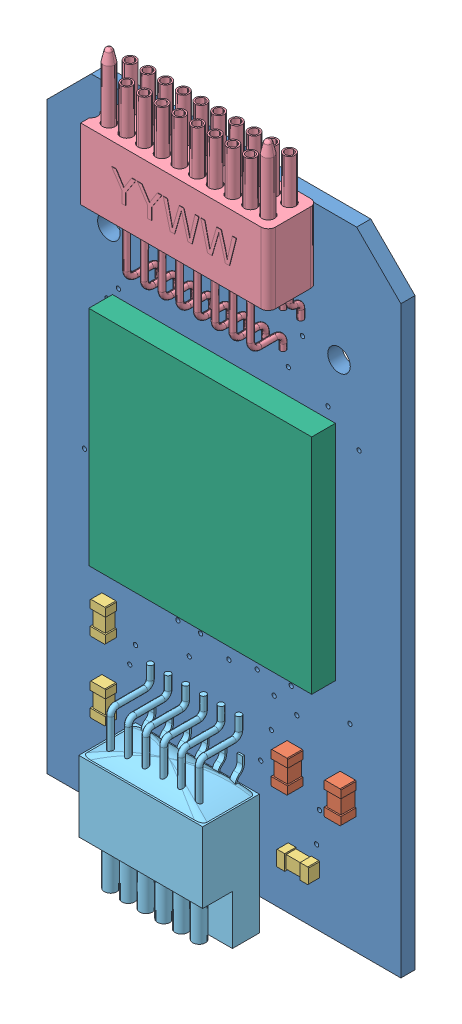
SolidWorks assembly RHD2132_headstage_16, configuration Default. Lengths in mm.
Overall size (12.7 26.11 2.55).
10 component instances, 6 part files, 20 mates.
Components (placement in the parent):
- rhd2132_headstage_16_PCB-1: rhd2132_headstage_16_PCB [Default] at origin size (12.7 22.54 0.51)
- 0402c_2320560-1: 0402c_2320560 [Default] at (10.795 4.7625 0.508) x (0 -1 0) z (0 0 1) size (1.15 0.6 0.55)
- 0402c_2320560-2: 0402c_2320560 [Default] at (8.89 4.7625 0.508) x (0 -1 0) z (0 0 1) size (1.15 0.6 0.55)
- 0402r_1430758-1: 0402r_1430758 [Default] at (1.905 20.3325 0.508) x (0 1 0) z (0 0 1) size (1.15 0.55 0.4)
- 0402r_1430758-2: 0402r_1430758 [Default] at (2.2225 3.4925 0.508) x (0 1 0) z (0 0 1) size (1.15 0.55 0.4)
- 0402r_1430758-3: 0402r_1430758 [Default] at (2.2225 6.0325 0.508) x (0 1 0) z (0 0 1) size (1.15 0.55 0.4)
- 0402r_1430758-4: 0402r_1430758 [Default] at (9.2075 1.905 0.508) size (1.15 0.55 0.4)
- A79041-001-1: A79041-001 [Default] at (6.3513 21.336 1.397) x (-1 0 0) z (0 1 0) size (6.73 2.08 7.44)
- A79623-001-1: A79623-001 [Default] at (5.3975 3.175 0.508) x (1 0 0) z (0 -1 0) size (4.45 2.05 6.53)
- QFN_8x8mm-1: QFN_8x8mm [Default] at (2.35 8.065 0.508) x (1 0 0) z (0 -1 0) size (8 0.85 8)
Mates (geometry in assembly coordinates):
- Coincident1: coincident anti-aligned: plane of rhd2132_headstage_16-1 through (0 0 0.508) normal (0 0 1); plane of QFN_8x8mm-1 through (2.35 8.065 0.508) normal (0 0 -1)
- Parallel1: parallel aligned: plane of rhd2132_headstage_16-1 through (0 0 0.508) normal (-1 0 0); plane of QFN_8x8mm-1 through (2.35 8.065 1.358) normal (-1 0 0)
- Coincident2: coincident anti-aligned: plane of rhd2132_headstage_16-1 through (0 0 0.508) normal (0 0 1); plane of A79041-001-1 through (9.7168 20.066 0.508) normal (0 0 -1)
- Parallel2: parallel aligned: plane of rhd2132_headstage_16-1 through (1.5875 22.5425 0.508) normal (0 1 0); plane of A79041-001-1 through (9.7168 22.606 2.286) normal (0 1 0)
- Coincident3: coincident anti-aligned: plane of rhd2132_headstage_16-1 through (0 0 0.508) normal (0 0 1); plane of A79623-001-1 through (5.3975 3.175 0.508) normal (0 0 -1)
- Parallel3: parallel aligned: plane of rhd2132_headstage_16-1 through (12.7 0 0.508) normal (0 -1 0); plane of A79623-001-1 through (7.62 -1.143 0.508) normal (0 -1 0)
- Distance1: distance = 0.0635 mm: line of A79041-001-1 through (9.4628 22.606 0.508) axis (-1 0 0); line of rhd2132_headstage_16-1 through (11.1125 22.5425 0.508) axis (-1 0 0)
- Distance2: distance = 1.3983 mm: point of rhd2132_headstage_16-1; line of A79041-001-1 through (2.9858 20.066 0.508) axis (0 1 0)
- Coincident6: coincident anti-aligned: plane of rhd2132_headstage_16-1 through (0 0 0.508) normal (0 0 1); plane of 0402r_1430758-1 through (1.08 20.3325 0.508) normal (0 0 -1)
- Parallel4: parallel aligned: plane of rhd2132_headstage_16-1 through (1.5875 22.5425 0.508) normal (0 1 0); plane of 0402r_1430758-1 through (2.155 20.9075 0.908) normal (0 1 0)
- Coincident7: coincident anti-aligned: plane of rhd2132_headstage_16-1 through (0 0 0.508) normal (0 0 1); plane of 0402r_1430758-3 through (1.3975 6.0325 0.508) normal (0 0 -1)
- Parallel5: parallel aligned: plane of rhd2132_headstage_16-1 through (12.7 0 0.508) normal (0 -1 0); plane of 0402r_1430758-3 through (1.9725 5.4575 0.908) normal (0 -1 0)
- Coincident8: coincident anti-aligned: plane of rhd2132_headstage_16-1 through (0 0 0.508) normal (0 0 1); plane of 0402r_1430758-2 through (1.3975 3.4925 0.508) normal (0 0 -1)
- Parallel6: parallel aligned: plane of rhd2132_headstage_16-1 through (12.7 0 0.508) normal (0 -1 0); plane of 0402r_1430758-2 through (1.9725 2.9175 0.908) normal (0 -1 0)
- Coincident9: coincident anti-aligned: plane of rhd2132_headstage_16-1 through (0 0 0.508) normal (0 0 1); plane of 0402r_1430758-4 through (9.2075 2.73 0.508) normal (0 0 -1)
- Parallel7: parallel aligned: plane of rhd2132_headstage_16-1 through (12.7 20.955 0.508) normal (1 0 0); plane of 0402r_1430758-4 through (9.7825 1.655 0.908) normal (1 0 0)
- Coincident10: coincident anti-aligned: plane of rhd2132_headstage_16-1 through (0 0 0.508) normal (0 0 1); plane of 0402c_2320560-2 through (9.74 4.7625 0.508) normal (0 0 -1)
- Parallel8: parallel aligned: plane of rhd2132_headstage_16-1 through (12.7 0 0.508) normal (0 -1 0); plane of 0402c_2320560-2 through (8.615 4.1875 1.058) normal (0 -1 0)
- Coincident11: coincident anti-aligned: plane of rhd2132_headstage_16-1 through (0 0 0.508) normal (0 0 1); plane of 0402c_2320560-1 through (11.645 4.7625 0.508) normal (0 0 -1)
- Parallel9: parallel aligned: plane of rhd2132_headstage_16-1 through (12.7 0 0.508) normal (0 -1 0); plane of 0402c_2320560-1 through (10.52 4.1875 1.058) normal (0 -1 0)
